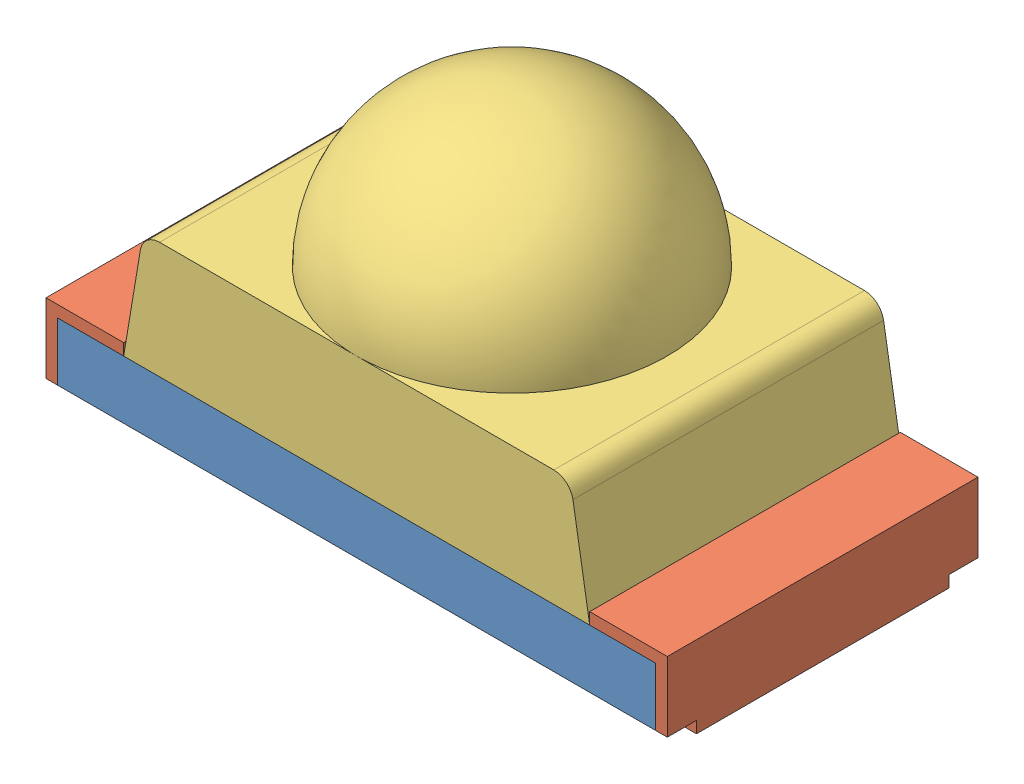
SolidWorks assembly LED0603O, configuration Default. Lengths in mm.
Overall size (1.6 0.88 0.8).
4 component instances, 3 part files, 9 mates.
Components (placement in the parent):
- LED0603-substrate-1: LED0603-substrate [Default] at (0 0.03 0) size (1.54 0.15 0.8)
- LED0603-clip-1: LED0603-clip [Default] at (-0.8 0.105 0) x (1 0 0) z (0 1 0) size (0.3 0.8 0.21)
- LED0603-clip-2: LED0603-clip [Default] at (0.8 0.105 0) x (-1 0 0) z (0 1 0) size (0.3 0.8 0.21)
- LED0603-lens-1: LED0603-lens [Default] at (0 0.18 0) size (1.2 0.7 0.8)
Mates (geometry in assembly coordinates):
- Coincident1: coincident aligned: plane of LED0603-substrate-1 through (0 0.03 0) normal (1 0 0)
- Coincident2: coincident aligned: plane of LED0603-substrate-1 through (0 0.03 0) normal (0 0 1)
- Distance1: distance = 0.03 mm aligned: plane of LED0603-substrate-1 through (0 0.03 0) normal (0 1 0)
- Coincident4: coincident anti-aligned: plane of LED0603-clip-1 through (-0.8 0.105 0) normal (0 0 -1)
- Coincident5: coincident anti-aligned: plane of LED0603-substrate-1 through (0 0.03 0) normal (0 -1 0); plane of LED0603-clip-1 through (-0.5 0.03 -0.4) normal (0 1 0)
- Coincident6: coincident anti-aligned: plane of LED0603-substrate-1 through (-0.77 0.18 0.4) normal (-1 0 0); plane of LED0603-clip-1 through (-0.77 0.18 -0.4) normal (1 0 0)
- Coincident7: coincident aligned: plane of LED0603-lens-1 through (0 0.18 0) normal (0 0 1)
- Coincident8: coincident aligned: plane of LED0603-lens-1 through (0 0.18 0) normal (1 0 0)
- Coincident9: coincident anti-aligned: plane of LED0603-substrate-1 through (0 0.18 0) normal (0 1 0); plane of LED0603-lens-1 through (0 0.18 0) normal (0 -1 0)
